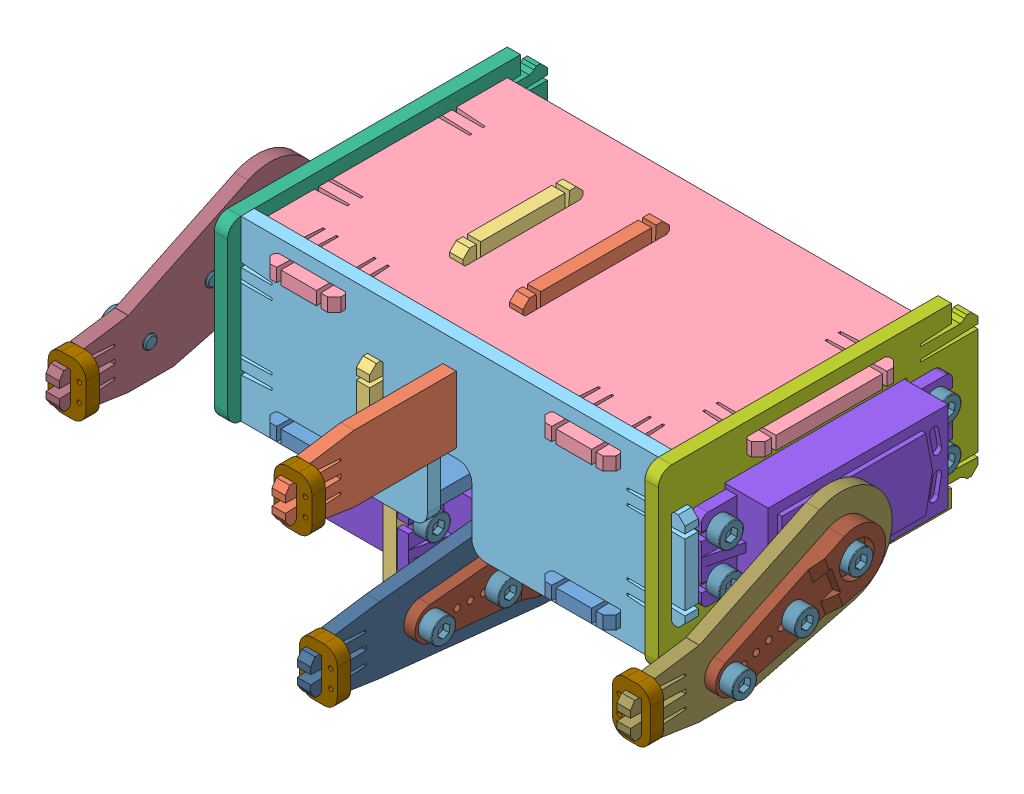
SolidWorks assembly mouth, configuration Default. Lengths in mm.
Overall size (142.6 64 107.5).
41 component instances, 14 part files, 78 mates.
Components (placement in the parent):
- mouth-frame-1-1: mouth-frame-1 [Default] at origin size (106 3 63)
- mouth-frame-2-1: mouth-frame-2 [Default] at origin size (3 40 98.5)
- mouth-frame-3-1: mouth-frame-3 [Default] at origin size (3 64 63)
- mouth-frame-4-1: mouth-frame-4 [Default] at origin size (106 3 63)
- mouth-frame-5-1: mouth-frame-5 [Default] at origin size (106 40 3)
- mouth-frame-6-1: mouth-frame-6 [Default] at origin size (3 40 72)
- mouth-frame-7-1: mouth-frame-7 [Default] at origin size (3 40 72)
- servo-standard-1: servo-standard [Default] at (23.1 0 0) x (0 0 -1) z (0 -1 0) size (58.5 43.2 20.3)
- servo-standard-2: servo-standard [Default] at (-41.9 -30.5 1) x (0 0 -1) z (0 -1 0) size (58.5 43.2 20.3)
- servo-standard-3: servo-standard [Default] at (-23.1 0 0) x (0 0 -1) z (0 1 0) size (58.5 43.2 20.3)
- textile-snap-2: textile-snap [Default] at (0.75 6.5 67) x (1 0 0) z (0 -1 0) size (8.5 3 12)
- lever-mid-towerpro-horn-1: lever-mid-towerpro-horn [Default] at (-2.2 -30.5 11.1) x (0 0 1) z (0 -1 0) size (65 3 23)
- servo-horn-towerpro-1-arm-1: servo-horn-towerpro-1-arm [Default] at (2.05 -30.5 11.1) x (0 1 0) z (0 0 -1) size (13 6.5 39)
- textile-snap-5: textile-snap [Default] at (0.05 -30.5 60.6) x (1 0 0) z (0 -1 0) size (8.5 3 12)
- lever-outer-l-towerpro-horn-1: lever-outer-l-towerpro-horn [Default] at (65.8 0 10.1) x (0 0 1) z (0 1 0) size (59 3 29)
- lever-outer-r-towerpro-horn-1: lever-outer-r-towerpro-horn [Default] at (-62.8 0 10.1) x (0 0 1) z (0 1 0) size (59 3 29)
- servo-horn-towerpro-1-arm-2: servo-horn-towerpro-1-arm [Default] at (67.05 0 10.1) x (0 0.939693 0.34202) z (0 0.34202 -0.939693) size (13 6.5 39)
- servo-horn-towerpro-1-arm-3: servo-horn-towerpro-1-arm [Default] at (-67.05 0 10.1) x (0 -0.939693 -0.34202) z (0 0.34202 -0.939693) size (13 6.5 39)
- textile-snap-6: textile-snap [Default] at (-63.55 -10 53.6) x (1 0 0) z (0 -1 0) size (8.5 3 12)
- textile-snap-7: textile-snap [Default] at (63.55 -10 53.6) x (-1 0 0) z (0 1 0) size (8.5 3 12)
- socket head cap screw_iso-1: socket head cap screw_iso [ISO 4762 M3 x 6 --- 6N] at (55.5 5 24.5) x (-1 0 0) z (0 -0.924225 -0.381849) size (9 5.5 5.5)
- socket head cap screw_iso-2: socket head cap screw_iso [ISO 4762 M3 x 6 --- 6N] at (55.5 -5 24.5) x (-1 0 0) z (0 -0.924225 -0.381849) size (9 5.5 5.5)
- socket head cap screw_iso-3: socket head cap screw_iso [ISO 4762 M3 x 6 --- 6N] at (55.5 5 -24.5) x (-1 0 0) z (0 -0.924225 -0.381849) size (9 5.5 5.5)
- socket head cap screw_iso-4: socket head cap screw_iso [ISO 4762 M3 x 6 --- 6N] at (55.5 -5 -24.5) x (-1 0 0) z (0 -0.924225 -0.381849) size (9 5.5 5.5)
- socket head cap screw_iso-5: socket head cap screw_iso [ISO 4762 M3 x 6 --- 6N] at (-9.5 -25.5 25.5) x (-1 0 0) z (0 -0.924225 -0.381849) size (9 5.5 5.5)
- socket head cap screw_iso-6: socket head cap screw_iso [ISO 4762 M3 x 6 --- 6N] at (-9.5 -35.5 25.5) x (-1 0 0) z (0 -0.924225 -0.381849) size (9 5.5 5.5)
- socket head cap screw_iso-7: socket head cap screw_iso [ISO 4762 M3 x 6 --- 6N] at (-9.5 -25.5 -23.5) x (-1 0 0) z (0 -0.924225 -0.381849) size (9 5.5 5.5)
- socket head cap screw_iso-8: socket head cap screw_iso [ISO 4762 M3 x 6 --- 6N] at (-9.5 -35.5 -23.5) x (-1 0 0) z (0 -0.924225 -0.381849) size (9 5.5 5.5)
- socket head cap screw_iso-9: socket head cap screw_iso [ISO 4762 M3 x 6 --- 6N] at (-55.5 5 24.5) size (9 5.5 5.5)
- socket head cap screw_iso-10: socket head cap screw_iso [ISO 4762 M3 x 6 --- 6N] at (-55.5 -5 24.5) size (9 5.5 5.5)
- socket head cap screw_iso-11: socket head cap screw_iso [ISO 4762 M3 x 6 --- 6N] at (-55.5 -5 -24.5) size (9 5.5 5.5)
- socket head cap screw_iso-12: socket head cap screw_iso [ISO 4762 M3 x 6 --- 6N] at (-55.5 5 -24.5) size (9 5.5 5.5)
- socket head cap screw_iso-25: socket head cap screw_iso [ISO 4762 M3 x 6 --- 6N] at (6.3 -30.5 40.1) x (-1 0 0) z (0 -0.924225 -0.381849) size (9 5.5 5.5)
- socket head cap screw_iso-26: socket head cap screw_iso [ISO 4762 M3 x 6 --- 6N] at (6.3 -30.5 25.1) x (-1 0 0) z (0 -0.924225 -0.381849) size (9 5.5 5.5)
- socket head cap screw_iso-27: socket head cap screw_iso [ISO 4762 M3 x 6 --- 6N] at (5.3 -30.5 11.1) x (-1 0 0) z (0 -0.924225 -0.381849) size (9 5.5 5.5)
- socket head cap screw_iso-28: socket head cap screw_iso [ISO 4762 M3 x 6 --- 6N] at (71.3 -9.9186 37.3511) x (-1 0 0) z (0 -0.924225 -0.381849) size (9 5.5 5.5)
- socket head cap screw_iso-29: socket head cap screw_iso [ISO 4762 M3 x 6 --- 6N] at (71.3 -4.7883 23.2557) x (-1 0 0) z (0 -0.924225 -0.381849) size (9 5.5 5.5)
- socket head cap screw_iso-30: socket head cap screw_iso [ISO 4762 M3 x 6 --- 6N] at (70.3 0 10.1) x (-1 0 0) z (0 -0.924225 -0.381849) size (9 5.5 5.5)
- socket head cap screw_iso-35: socket head cap screw_iso [ISO 4762 M3 x 6 --- 6N] at (-70.3 0 10.1) size (9 5.5 5.5)
- socket head cap screw_iso-36: socket head cap screw_iso [ISO 4762 M3 x 6 --- 6N] at (-71.3 -4.7883 23.2557) size (9 5.5 5.5)
- socket head cap screw_iso-37: socket head cap screw_iso [ISO 4762 M3 x 6 --- 6N] at (-71.3 -9.9186 37.3511) size (9 5.5 5.5)
Mates (geometry in assembly coordinates):
- Coincident1: coincident anti-aligned: plane of mouth-frame-7-1 through (50 0 0) normal (1 0 0); plane of servo-standard-1 through (50 0 0) normal (-1 0 0)
- Concentric1: concentric: cylinder of mouth-frame-7-1 through (50 -5 24.5) axis (-1 0 0) radius 1.25; point of servo-standard-1
- Concentric2: concentric: cylinder of mouth-frame-7-1 through (50 5 -24.5) axis (-1 0 0) radius 1.25; point of servo-standard-1
- Concentric3: concentric anti-aligned: cylinder of mouth-frame-7-1 through (50 5 24.5) axis (-1 0 0) radius 1.25; cylinder of socket head cap screw_iso-1 through (87.25 5 24.5) axis (1 0 0) radius 1.5
- Coincident5: coincident anti-aligned: plane of servo-standard-1 through (52.5 0 0) normal (1 0 0); plane of socket head cap screw_iso-1 through (52.5 6.0501 21.9584) normal (-1 0 0)
- Concentric4: concentric anti-aligned: cylinder of mouth-frame-7-1 through (50 -5 24.5) axis (-1 0 0) radius 1.25; cylinder of socket head cap screw_iso-2 through (87.25 -5 24.5) axis (1 0 0) radius 1.5
- Coincident6: coincident anti-aligned: plane of servo-standard-1 through (52.5 0 0) normal (1 0 0); plane of socket head cap screw_iso-2 through (52.5 -3.9499 21.9584) normal (-1 0 0)
- Concentric5: concentric anti-aligned: cylinder of mouth-frame-7-1 through (50 5 -24.5) axis (-1 0 0) radius 1.25; cylinder of socket head cap screw_iso-3 through (87.25 5 -24.5) axis (1 0 0) radius 1.5
- Coincident7: coincident anti-aligned: plane of servo-standard-1 through (52.5 0 0) normal (1 0 0); plane of socket head cap screw_iso-3 through (52.5 6.0501 -27.0416) normal (-1 0 0)
- Concentric6: concentric anti-aligned: cylinder of mouth-frame-7-1 through (50 -5 -24.5) axis (-1 0 0) radius 1.25; cylinder of socket head cap screw_iso-4 through (87.25 -5 -24.5) axis (1 0 0) radius 1.5
- Coincident8: coincident anti-aligned: plane of servo-standard-1 through (52.5 0 0) normal (1 0 0); plane of socket head cap screw_iso-4 through (52.5 -3.9499 -27.0416) normal (-1 0 0)
- Coincident9: coincident anti-aligned: plane of servo-standard-2 through (-12.5 -30.5 1) normal (1 0 0); plane of socket head cap screw_iso-5 through (-12.5 -24.4499 22.9584) normal (-1 0 0)
- Coincident10: coincident anti-aligned: plane of servo-standard-2 through (-12.5 -30.5 1) normal (1 0 0); plane of socket head cap screw_iso-6 through (-12.5 -34.4499 22.9584) normal (-1 0 0)
- Coincident11: coincident anti-aligned: plane of servo-standard-2 through (-12.5 -30.5 1) normal (1 0 0); plane of socket head cap screw_iso-7 through (-12.5 -24.4499 -26.0416) normal (-1 0 0)
- Coincident12: coincident anti-aligned: plane of servo-standard-2 through (-12.5 -30.5 1) normal (1 0 0); plane of socket head cap screw_iso-8 through (-12.5 -34.4499 -26.0416) normal (-1 0 0)
- Coincident13: coincident anti-aligned: plane of mouth-frame-3-1 through (-15 0 0) normal (1 0 0); plane of servo-standard-2 through (-15 -30.5 1) normal (-1 0 0)
- Concentric7: concentric: cylinder of mouth-frame-3-1 through (-15 -35.5 25.5) axis (-1 0 0) radius 1.25; point of servo-standard-2
- Concentric8: concentric: cylinder of mouth-frame-3-1 through (-15 -25.5 -23.5) axis (-1 0 0) radius 1.25; point of servo-standard-2
- Concentric9: concentric anti-aligned: cylinder of mouth-frame-3-1 through (-15 -25.5 25.5) axis (-1 0 0) radius 1.25; cylinder of socket head cap screw_iso-5 through (22.25 -25.5 25.5) axis (1 0 0) radius 1.5
- Concentric10: concentric anti-aligned: cylinder of mouth-frame-3-1 through (-15 -35.5 25.5) axis (-1 0 0) radius 1.25; cylinder of socket head cap screw_iso-6 through (22.25 -35.5 25.5) axis (1 0 0) radius 1.5
- Concentric11: concentric anti-aligned: cylinder of mouth-frame-3-1 through (-15 -25.5 -23.5) axis (-1 0 0) radius 1.25; cylinder of socket head cap screw_iso-7 through (22.25 -25.5 -23.5) axis (1 0 0) radius 1.5
- Concentric12: concentric anti-aligned: cylinder of mouth-frame-3-1 through (-15 -35.5 -23.5) axis (-1 0 0) radius 1.25; cylinder of socket head cap screw_iso-8 through (22.25 -35.5 -23.5) axis (1 0 0) radius 1.5
- Coincident14: coincident anti-aligned: plane of servo-standard-3 through (-52.5 0 0) normal (-1 0 0); plane of socket head cap screw_iso-9 through (-52.5 7.75 24.5) normal (1 0 0)
- Coincident15: coincident anti-aligned: plane of servo-standard-3 through (-52.5 0 0) normal (-1 0 0); plane of socket head cap screw_iso-10 through (-52.5 -2.25 24.5) normal (1 0 0)
- Coincident16: coincident anti-aligned: plane of servo-standard-3 through (-52.5 0 0) normal (-1 0 0); plane of socket head cap screw_iso-11 through (-52.5 -2.25 -24.5) normal (1 0 0)
- Coincident17: coincident anti-aligned: plane of servo-standard-3 through (-52.5 0 0) normal (-1 0 0); plane of socket head cap screw_iso-12 through (-52.5 7.75 -24.5) normal (1 0 0)
- Coincident18: coincident anti-aligned: plane of mouth-frame-6-1 through (-50 0 0) normal (-1 0 0); plane of servo-standard-3 through (-50 0 0) normal (1 0 0)
- Concentric13: concentric: cylinder of mouth-frame-6-1 through (-50 5 24.5) axis (1 0 0) radius 1.25; point of servo-standard-3
- Concentric14: concentric: cylinder of mouth-frame-6-1 through (-50 -5 -24.5) axis (1 0 0) radius 1.25; point of servo-standard-3
- Concentric15: concentric anti-aligned: cylinder of mouth-frame-6-1 through (-50 5 24.5) axis (1 0 0) radius 1.25; cylinder of socket head cap screw_iso-9 through (-87.25 5 24.5) axis (-1 0 0) radius 1.5
- Concentric16: concentric anti-aligned: cylinder of mouth-frame-6-1 through (-50 -5 24.5) axis (1 0 0) radius 1.25; cylinder of socket head cap screw_iso-10 through (-87.25 -5 24.5) axis (-1 0 0) radius 1.5
- Concentric17: concentric anti-aligned: cylinder of mouth-frame-6-1 through (-50 -5 -24.5) axis (1 0 0) radius 1.25; cylinder of socket head cap screw_iso-11 through (-87.25 -5 -24.5) axis (-1 0 0) radius 1.5
- Concentric18: concentric anti-aligned: cylinder of mouth-frame-6-1 through (-50 5 -24.5) axis (1 0 0) radius 1.25; cylinder of socket head cap screw_iso-12 through (-87.25 5 -24.5) axis (-1 0 0) radius 1.5
- Coincident45: coincident anti-aligned: plane of mouth-frame-2-1 through (1.5 0 65.5) normal (0 0 1); plane of textile-snap-2 through (0.75 6.5 65.5) normal (0 0 -1)
- Coincident46: coincident anti-aligned: plane of mouth-frame-2-1 through (1.5 0 0) normal (1 0 0); plane of textile-snap-2 through (1.5 9.5 68.5) normal (-1 0 0)
- Coincident47: coincident anti-aligned: plane of mouth-frame-2-1 through (1.5 9.5 0) normal (0 1 0); plane of textile-snap-2 through (-1.5 9.5 68.5) normal (0 -1 0)
- Concentric41: concentric aligned: cylinder of lever-mid-towerpro-horn-1 through (0.8 -30.5 25.1) axis (-1 0 0) radius 1.25; cylinder of servo-horn-towerpro-1-arm-1 through (4.3 -30.5 25.1) axis (-1 0 0) radius 0.75
- Concentric42: concentric aligned: cylinder of lever-mid-towerpro-horn-1 through (0.8 -30.5 40.1) axis (-1 0 0) radius 1.25; cylinder of servo-horn-towerpro-1-arm-1 through (4.3 -30.5 40.1) axis (-1 0 0) radius 0.75
- Coincident54: coincident anti-aligned: plane of lever-mid-towerpro-horn-1 through (0.8 -30.5 11.1) normal (1 0 0); plane of servo-horn-towerpro-1-arm-1 through (0.8 -37.5 43.6) normal (-1 0 0)
- Coincident55: coincident anti-aligned: plane of lever-mid-towerpro-horn-1 through (0.8 -30.5 59.1) normal (0 0 1); plane of textile-snap-5 through (0.05 -30.5 59.1) normal (0 0 -1)
- Coincident56: coincident anti-aligned: plane of lever-mid-towerpro-horn-1 through (0.8 -30.5 11.1) normal (1 0 0); plane of textile-snap-5 through (0.8 -27.5 62.1) normal (-1 0 0)
- Coincident57: coincident anti-aligned: plane of lever-mid-towerpro-horn-1 through (0.8 -27.5 11.1) normal (0 1 0); plane of textile-snap-5 through (-2.2 -27.5 62.1) normal (0 -1 0)
- Concentric43: concentric anti-aligned: cylinder of servo-horn-towerpro-1-arm-1 through (4.3 -30.5 40.1) axis (-1 0 0) radius 0.75; cylinder of socket head cap screw_iso-25 through (38.05 -30.5 40.1) axis (1 0 0) radius 1.5
- Coincident58: coincident anti-aligned: plane of servo-horn-towerpro-1-arm-1 through (3.3 -37.5 43.6) normal (1 0 0); plane of socket head cap screw_iso-25 through (3.3 -29.4499 37.5584) normal (-1 0 0)
- Concentric44: concentric anti-aligned: cylinder of servo-horn-towerpro-1-arm-1 through (4.3 -30.5 25.1) axis (-1 0 0) radius 0.75; cylinder of socket head cap screw_iso-26 through (38.05 -30.5 25.1) axis (1 0 0) radius 1.5
- Coincident59: coincident anti-aligned: plane of servo-horn-towerpro-1-arm-1 through (3.3 -37.5 43.6) normal (1 0 0); plane of socket head cap screw_iso-26 through (3.3 -29.4499 22.5584) normal (-1 0 0)
- Concentric45: concentric anti-aligned: cylinder of servo-horn-towerpro-1-arm-1 through (4.3 -30.5 11.1) axis (-1 0 0) radius 1.5; cylinder of socket head cap screw_iso-27 through (37.05 -30.5 11.1) axis (1 0 0) radius 1.5
- Coincident60: coincident anti-aligned: plane of servo-horn-towerpro-1-arm-1 through (2.3 -30.5 11.1) normal (1 0 0); plane of socket head cap screw_iso-27 through (2.3 -29.4499 8.5584) normal (-1 0 0)
- Concentric46: concentric aligned: cylinder of servo-standard-2 through (1.3 -30.5 11.1) axis (-1 0 0) radius 3; cylinder of servo-horn-towerpro-1-arm-1 through (1.3 -30.5 11.1) axis (-1 0 0) radius 3
- Coincident62: coincident anti-aligned: plane of servo-standard-2 through (1.3 -30.5 11.1) normal (1 0 0); plane of servo-horn-towerpro-1-arm-1 through (1.3 -30.5 11.1) normal (-1 0 0)
- Concentric47: concentric anti-aligned: cylinder of lever-outer-l-towerpro-horn-1 through (62.8 -4.7883 23.2557) axis (1 0 0) radius 1.25; cylinder of servo-horn-towerpro-1-arm-2 through (69.3 -4.7883 23.2557) axis (-1 0 0) radius 0.75
- Concentric48: concentric anti-aligned: cylinder of lever-outer-l-towerpro-horn-1 through (62.8 -9.9186 37.3511) axis (1 0 0) radius 1.25; cylinder of servo-horn-towerpro-1-arm-2 through (69.3 -9.9186 37.3511) axis (-1 0 0) radius 0.75
- Coincident63: coincident anti-aligned: plane of lever-outer-l-towerpro-horn-1 through (65.8 0 10.1) normal (1 0 0); plane of servo-horn-towerpro-1-arm-2 through (65.8 -17.6935 38.2459) normal (-1 0 0)
- Concentric49: concentric anti-aligned: cylinder of servo-horn-towerpro-1-arm-2 through (69.3 -9.9186 37.3511) axis (-1 0 0) radius 0.75; cylinder of socket head cap screw_iso-28 through (103.05 -9.9186 37.3511) axis (1 0 0) radius 1.5
- Coincident64: coincident anti-aligned: plane of servo-horn-towerpro-1-arm-2 through (68.3 -17.6935 38.2459) normal (1 0 0); plane of socket head cap screw_iso-28 through (68.3 -8.8685 34.8095) normal (-1 0 0)
- Concentric50: concentric anti-aligned: cylinder of servo-horn-towerpro-1-arm-2 through (69.3 -4.7883 23.2557) axis (-1 0 0) radius 0.75; cylinder of socket head cap screw_iso-29 through (103.05 -4.7883 23.2557) axis (1 0 0) radius 1.5
- Coincident65: coincident anti-aligned: plane of servo-horn-towerpro-1-arm-2 through (68.3 -17.6935 38.2459) normal (1 0 0); plane of socket head cap screw_iso-29 through (68.3 -3.7382 20.7141) normal (-1 0 0)
- Concentric51: concentric anti-aligned: cylinder of servo-horn-towerpro-1-arm-2 through (69.3 0 10.1) axis (-1 0 0) radius 1.5; cylinder of socket head cap screw_iso-30 through (102.05 0 10.1) axis (1 0 0) radius 1.5
- Coincident66: coincident anti-aligned: plane of servo-horn-towerpro-1-arm-2 through (67.3 0 10.1) normal (1 0 0); plane of socket head cap screw_iso-30 through (67.3 1.0501 7.5584) normal (-1 0 0)
- Concentric55: concentric aligned: cylinder of lever-outer-r-towerpro-horn-1 through (-65.8 -4.7883 23.2557) axis (1 0 0) radius 1.25; cylinder of servo-horn-towerpro-1-arm-3 through (-69.3 -4.7883 23.2557) axis (1 0 0) radius 0.75
- Concentric56: concentric aligned: cylinder of lever-outer-r-towerpro-horn-1 through (-65.8 -9.9186 37.3511) axis (1 0 0) radius 1.25; cylinder of servo-horn-towerpro-1-arm-3 through (-69.3 -9.9186 37.3511) axis (1 0 0) radius 0.75
- Coincident70: coincident anti-aligned: plane of lever-outer-r-towerpro-horn-1 through (-65.8 0 10.1) normal (-1 0 0); plane of servo-horn-towerpro-1-arm-3 through (-65.8 -4.5378 43.0342) normal (1 0 0)
- Concentric57: concentric anti-aligned: cylinder of servo-horn-towerpro-1-arm-3 through (-69.3 0 10.1) axis (1 0 0) radius 1.5; cylinder of socket head cap screw_iso-35 through (-102.05 0 10.1) axis (-1 0 0) radius 1.5
- Coincident71: coincident anti-aligned: plane of servo-horn-towerpro-1-arm-3 through (-67.3 0 10.1) normal (-1 0 0); plane of socket head cap screw_iso-35 through (-67.3 2.75 10.1) normal (1 0 0)
- Concentric58: concentric anti-aligned: cylinder of servo-horn-towerpro-1-arm-3 through (-69.3 -4.7883 23.2557) axis (1 0 0) radius 0.75; cylinder of socket head cap screw_iso-36 through (-103.05 -4.7883 23.2557) axis (-1 0 0) radius 1.5
- Coincident72: coincident anti-aligned: plane of servo-horn-towerpro-1-arm-3 through (-68.3 -4.5378 43.0342) normal (-1 0 0); plane of socket head cap screw_iso-36 through (-68.3 -2.0383 23.2557) normal (1 0 0)
- Concentric59: concentric anti-aligned: cylinder of servo-horn-towerpro-1-arm-3 through (-69.3 -9.9186 37.3511) axis (1 0 0) radius 0.75; cylinder of socket head cap screw_iso-37 through (-103.05 -9.9186 37.3511) axis (-1 0 0) radius 1.5
- Coincident73: coincident anti-aligned: plane of servo-horn-towerpro-1-arm-3 through (-68.3 -4.5378 43.0342) normal (-1 0 0); plane of socket head cap screw_iso-37 through (-68.3 -7.1686 37.3511) normal (1 0 0)
- Coincident74: coincident anti-aligned: plane of lever-outer-r-towerpro-horn-1 through (-65.8 0 52.1) normal (0 0 1); plane of textile-snap-6 through (-63.55 -10 52.1) normal (0 0 -1)
- Coincident75: coincident anti-aligned: plane of lever-outer-r-towerpro-horn-1 through (-62.8 0 10.1) normal (1 0 0); plane of textile-snap-6 through (-62.8 -7 55.1) normal (-1 0 0)
- Coincident76: coincident anti-aligned: plane of lever-outer-r-towerpro-horn-1 through (-65.8 -7 10.1) normal (0 1 0); plane of textile-snap-6 through (-65.8 -7 55.1) normal (0 -1 0)
- Concentric60: concentric aligned: cylinder of servo-standard-3 through (-66.3 0 10.1) axis (1 0 0) radius 3; cylinder of servo-horn-towerpro-1-arm-3 through (-66.3 0 10.1) axis (1 0 0) radius 3
- Coincident77: coincident anti-aligned: plane of servo-standard-3 through (-66.3 0 10.1) normal (-1 0 0); plane of servo-horn-towerpro-1-arm-3 through (-66.3 0 10.1) normal (1 0 0)
- Concentric61: concentric aligned: cylinder of servo-standard-1 through (66.3 0 10.1) axis (-1 0 0) radius 3; cylinder of servo-horn-towerpro-1-arm-2 through (66.3 0 10.1) axis (-1 0 0) radius 3
- Coincident78: coincident anti-aligned: plane of servo-standard-1 through (66.3 0 10.1) normal (1 0 0); plane of servo-horn-towerpro-1-arm-2 through (66.3 0 10.1) normal (-1 0 0)
- Coincident79: coincident anti-aligned: plane of lever-outer-l-towerpro-horn-1 through (62.8 0 52.1) normal (0 0 1); plane of textile-snap-7 through (63.55 -10 52.1) normal (0 0 -1)
- Coincident80: coincident anti-aligned: plane of lever-outer-l-towerpro-horn-1 through (62.8 0 10.1) normal (-1 0 0); plane of textile-snap-7 through (62.8 -13 55.1) normal (1 0 0)
- Coincident81: coincident anti-aligned: plane of lever-outer-l-towerpro-horn-1 through (62.8 -13 10.1) normal (0 -1 0); plane of textile-snap-7 through (65.8 -13 55.1) normal (0 1 0)
